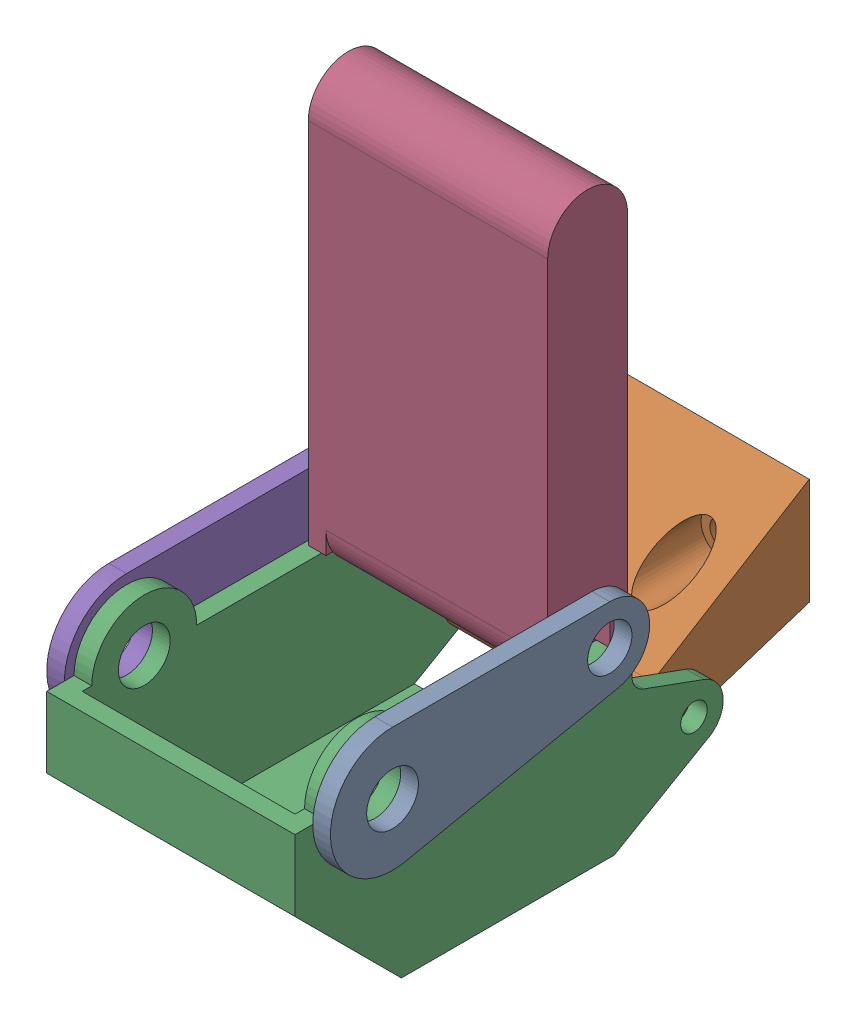
SolidWorks assembly Left Side Leg, configuration Default. Lengths in mm.
Overall size (25.81 53.23 49.2).
5 component instances, 4 part files, 12 mates.
Components (placement in the parent):
- Leg Attachment Part 1-1: Leg Attachment Part 1 [Default] at origin size (1.61 11.29 29.04)
- Leg Attachment Part 2-1: Leg Attachment Part 2 [Default] at (-4.0323 -8.8722 -11.9323) size (17.74 13.72 15.56)
- Leg Attachment Part 3-1: Leg Attachment Part 3 [Default] at (-24.196 -7.8816 1.351) x (0 0 -1) z (1 0 0) size (38.95 20.91 22.58)
- Leg Attachment Part 4-1: Leg Attachment Part 4 [Default] at (-12.9045 17.7444 -5.3156) x (1 0 0) z (0 -1 0) size (21.78 7.26 38.71)
- Leg Attachment Part 1-2: Leg Attachment Part 1 [Default] at (-24.196 0 0) size (1.61 11.29 29.04)
Mates (geometry in assembly coordinates):
- Coincident40: coincident: plane of assembly; plane of assembly; plane of Leg Attachment Part 1-1 through (-1.6129 0 14.4456) normal (-1 0 0); plane of Leg Attachment Part 3-1 through (-1.6129 0 14.4456) normal (1 0 0)
- Concentric31: concentric: cylinder of assembly; cylinder of assembly; cylinder of Leg Attachment Part 1-1 through (-1.6129 0 14.4456) axis (1 0 0) radius 2.3546; cylinder of Leg Attachment Part 3-1 through (-24.196 0 14.4456) axis (1 0 0) radius 2.3546
- Concentric33: concentric: cylinder of assembly; cylinder of assembly; cylinder of Leg Attachment Part 1-1 through (-1.6129 2.0168 -5.3156) axis (1 0 0) radius 2.0168; cylinder of Leg Attachment Part 4-1 through (-23.7922 2.0168 -5.3156) axis (1 0 0) radius 2.0168
- Width10: width: plane of assembly; plane of assembly; plane of assembly; plane of assembly; plane of Leg Attachment Part 4-1 through (-2.0168 2.0168 -5.3156) normal (1 0 0); plane of Leg Attachment Part 4-1 through (-23.7922 2.0168 -5.3156) normal (-1 0 0); plane of Leg Attachment Part 1-1 through (-1.6129 0 14.4456) normal (-1 0 0); plane of Leg Attachment Part 1-2 through (-24.196 0 14.4456) normal (1 0 0)
- Parallel20: parallel: plane of assembly; plane of assembly; plane of Leg Attachment Part 1-1 through (-1.6129 5.6464 14.4456) normal (0 1 0); plane of Leg Attachment Part 3-1 through (-1.6129 -16.1315 12.0275) normal (0 -1 0)
- Parallel19: parallel: plane of assembly; plane of assembly; plane of Leg Attachment Part 2-1 through (-21.7767 2.1895 -27.4949) normal (0 0 -1); plane of Leg Attachment Part 4-1 through (-23.7922 2.0168 -8.9453) normal (0 0 -1)
- Coincident43: coincident: cylinder of assembly; circle of assembly; circle of ?; cylinder of Leg Attachment Part 2-1 through (-21.7767 -8.8722 -14.5892) axis (1 0 0) radius 1.209; circle of Leg Attachment Part 3-1; circle of ?; circle of ?
- Width11: width: plane of assembly; plane of assembly; plane of assembly; plane of assembly; circle of ?; plane of Leg Attachment Part 2-1 through (-4.0323 -8.8722 -14.5892) normal (1 0 0); plane of Leg Attachment Part 2-1 through (-21.7767 -8.8722 -14.5892) normal (-1 0 0); plane of Leg Attachment Part 3-1 through (-3.2258 0 14.4456) normal (-1 0 0); circle of ?; circle of ?; plane of Leg Attachment Part 3-1 through (-22.5831 0 14.4456) normal (1 0 0); circle of ?; circle of ?
- Coincident41: coincident: plane of assembly; plane of assembly; plane of Leg Attachment Part 3-1 through (-24.196 0 14.4456) normal (-1 0 0); circle of ?; circle of ?; plane of Leg Attachment Part 1-2 through (-24.196 0 14.4456) normal (1 0 0)
- Concentric29: concentric: cylinder of assembly; circle of ?; circle of ?; cylinder of assembly; cylinder of Leg Attachment Part 3-1 through (-24.196 0 14.4456) axis (1 0 0) radius 2.3546; circle of ?; circle of ?; cylinder of Leg Attachment Part 1-2 through (-25.8089 0 14.4456) axis (1 0 0) radius 2.3546
- Coincident42: coincident: plane of assembly; plane of assembly; plane of Leg Attachment Part 3-1 through (-1.6129 0 9.6704) normal (0 1 0); circle of ?; circle of ?; plane of Leg Attachment Part 4-1 through (-22.1793 0 -1.686) normal (0 -1 0)
- Concentric32: concentric: cylinder of assembly; cylinder of assembly; cylinder of Leg Attachment Part 4-1 through (-23.7922 2.0168 -5.3156) axis (1 0 0) radius 2.0168; cylinder of Leg Attachment Part 1-2 through (-25.8089 2.0168 -5.3156) axis (1 0 0) radius 2.0168
